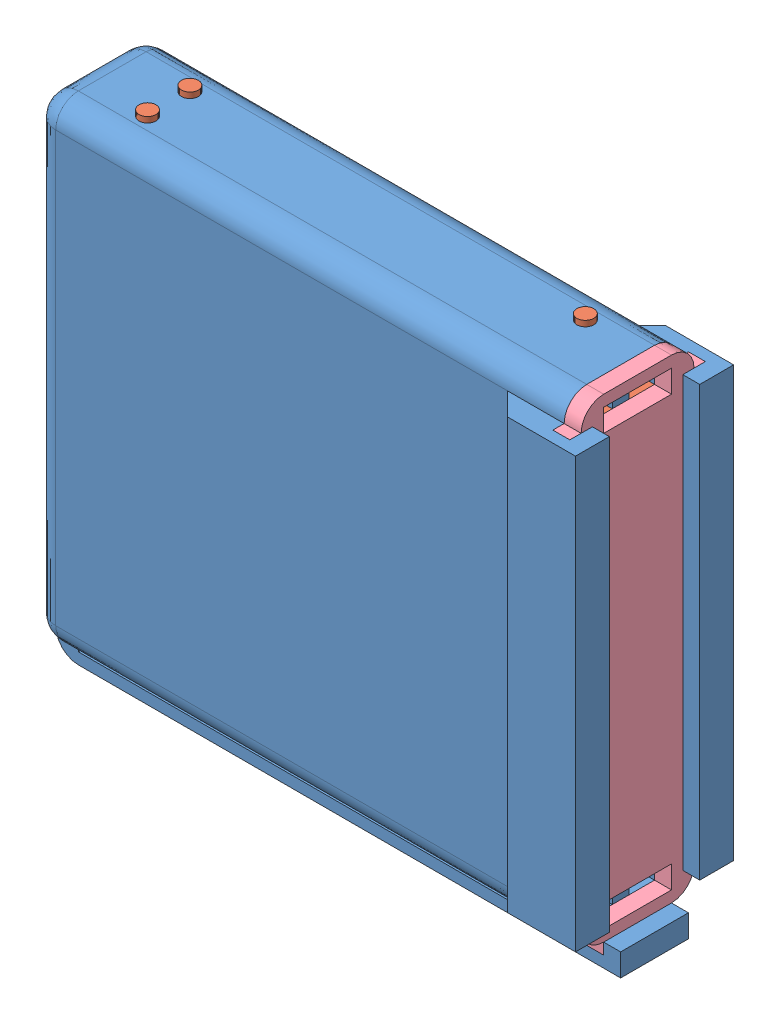
SolidWorks assembly Workspace, configuration Domyślna. Lengths in mm.
Overall size (50 44.5 14).
6 component instances, 4 part files, 15 mates.
Components (placement in the parent):
- FingerUnit-1: FingerUnit [Domyślna] at origin size (50 44 14)
- Potentiometer-1: Potentiometer [Domyślna] at (47 39 1) x (0 0 1) z (1 0 0) size (8 15 45)
- Head-1: Head [Domyślna] at (32.4 11.5 1.25) x (0 0 1) z (-1 0 0) size (7.5 10 14.6)
- Potentiometer-3: Potentiometer [Domyślna] at (47 3 9) x (0 0 -1) z (1 0 0) size (8 15 45)
- Head-3: Head [Domyślna] at (32.4 30.5 8.75) x (0 0 -1) z (-1 0 0) size (7.5 10 14.6)
- FingerUnit-Backcover-1: FingerUnit-Backcover [Domyślna] at (47 42 0) x (0 0 1) z (1 0 0) size (12 43 1.5)
Mates (geometry in assembly coordinates):
- Wspólnie1: coincident anti-aligned: plane of Potentiometer-1 through (42.2 27.5 4) normal (1 0 0); plane of Head-3 through (42.2 27 6) normal (-1 0 0)
- Wspólnie2: coincident anti-aligned: plane of Potentiometer-1 through (47 32 1) normal (0 -1 0); plane of Head-3 through (32.4 32 8.75) normal (0 1 0)
- Wspólnie3: coincident anti-aligned: plane of Potentiometer-1 through (42.2 27.5 6) normal (0 0 1); plane of Head-3 through (42.2 27 6) normal (0 0 -1)
- Wspólnie4: coincident anti-aligned: plane of FingerUnit-1 through (2 42 10) normal (1 0 0); plane of Potentiometer-1 through (2 32 1) normal (-1 0 0)
- Wspólnie5: coincident anti-aligned: plane of FingerUnit-1 through (47 42 9) normal (0 0 -1); plane of Potentiometer-1 through (47 32 9) normal (0 0 1)
- Wspólnie7: coincident anti-aligned: plane of FingerUnit-1 through (47 32 1) normal (0 1 0); plane of Potentiometer-1 through (47 32 1) normal (0 -1 0)
- Wspólnie8: coincident anti-aligned: plane of Head-1 through (42.2 15 6) normal (0 0 -1); plane of Potentiometer-3 through (42.2 14.5 6) normal (0 0 1)
- Wspólnie9: coincident anti-aligned: plane of Head-1 through (37.2 15 4) normal (1 0 0); plane of Potentiometer-3 through (37.2 14.5 6) normal (-1 0 0)
- Wspólnie10: coincident anti-aligned: plane of Head-1 through (32.4 10 1.25) normal (0 -1 0); plane of Potentiometer-3 through (47 10 9) normal (0 1 0)
- Wspólnie11: coincident anti-aligned: plane of FingerUnit-1 through (0 0 1) normal (0 0 1); plane of Potentiometer-3 through (47 10 1) normal (0 0 -1)
- Wspólnie12: coincident anti-aligned: plane of FingerUnit-1 through (2 42 10) normal (1 0 0); plane of Potentiometer-3 through (2 10 9) normal (-1 0 0)
- Wspólnie13: coincident anti-aligned: plane of FingerUnit-1 through (47 3 9) normal (0 1 0); plane of Potentiometer-3 through (47 3 9) normal (0 -1 0)
- Wspólnie14: coincident: plane of FingerUnit-1 through (0 -1 0) normal (0 1 0); plane of FingerUnit-Backcover-1 through (56.0916 -1 0) normal (0 -1 0)
- Wspólnie15: coincident: plane of FingerUnit-1 through (48.5 -1 11) normal (0 0 -1); plane of FingerUnit-Backcover-1 through (56.0916 42 11) normal (0 0 1)
- Wspólnie16: coincident anti-aligned: plane of FingerUnit-1 through (48.5 -1 -1) normal (-1 0 0); plane of FingerUnit-Backcover-1 through (48.5 42 0) normal (1 0 0)
